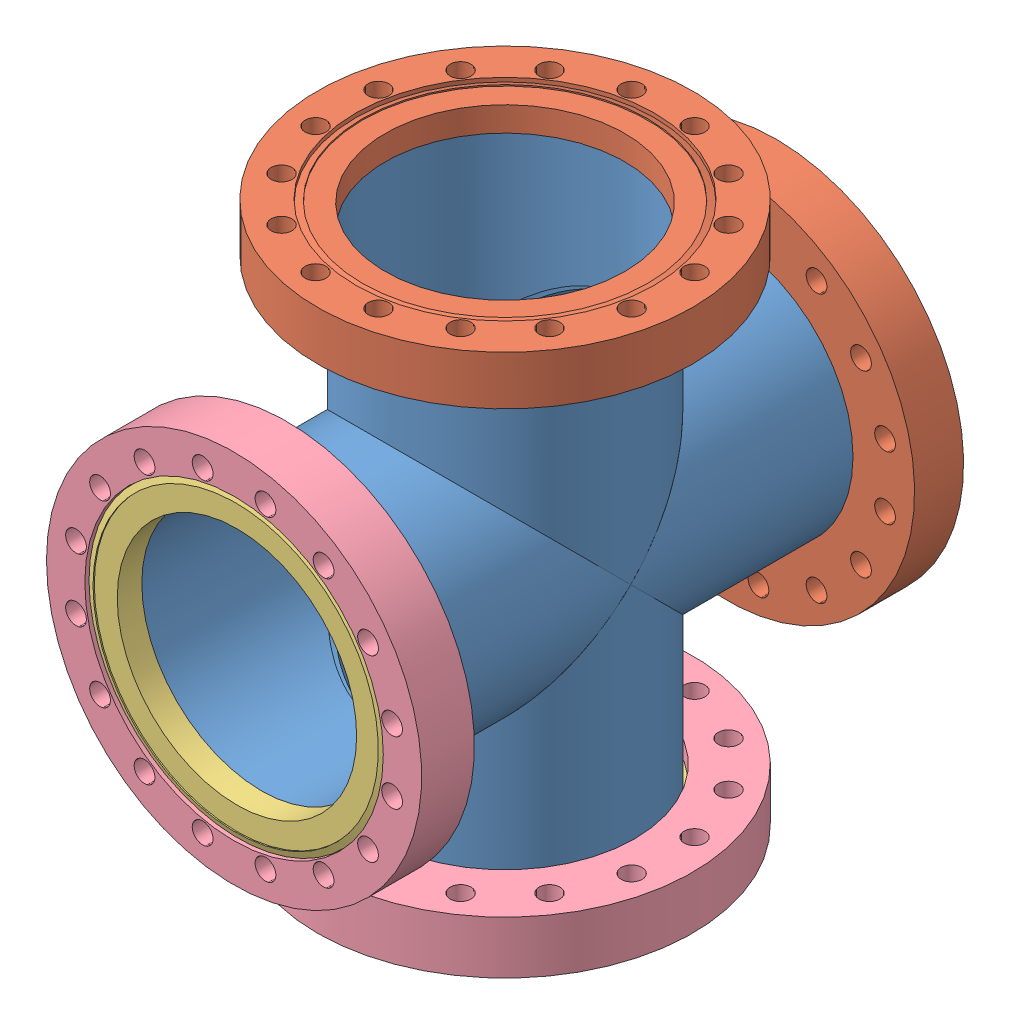
SolidWorks assembly 405033, configuration Default. Lengths in mm.
Overall size (151.64 219.05 219.05).
10 component instances, 4 part files, 0 mates.
Components (placement in the parent):
- 405033-001-1: 405033-001 [Default] at origin size (103.56 103.56 197.83)
- 405033-001-2: 405033-001 [Default] at (0 -98.425 98.425) x (1 0 0) z (0 1 0) size (103.56 103.56 197.83)
- 110026 (6.0 X 4.0 NR)-1: 110026 (6.0 X 4.0 NR) [Default] at (0 109.5248 98.425) x (0 -1 0) z (0 0 1) size (19.81 151.64 151.64)
- 110026 (6.0 X 4.0 NR)-2: 110026 (6.0 X 4.0 NR) [Default] at (0 0 -11.0998) x (0 0 1) z (-1 0 0) size (19.81 151.64 151.64)
- 100026 (6.0 X 4.0 R)-1: 100026 (6.0 X 4.0 R) [Default] at (0 0 193.6496) x (0 0 1) z (-1 0 0) size (21.34 151.64 151.64)
  - 100026 (6.0 X 4.0 INS)-1: 100026 (6.0 X 4.0 INS) [Default] at origin size (13.64 120.4 120.4)
  - 100026 (6.0 X 4.0 REC)-1: 100026 (6.0 X 4.0 REC) [Default] at (-7.0358 0 0) x (1 0 0) z (0 0 -1) size (21.34 151.64 151.64)
- 100026 (6.0 X 4.0 R)-2: 100026 (6.0 X 4.0 R) [Default] at (0 -95.2246 98.425) x (0 -1 0) z (0 0 1) size (21.34 151.64 151.64)
  - 100026 (6.0 X 4.0 INS)-1: 100026 (6.0 X 4.0 INS) [Default] at origin size (13.64 120.4 120.4)
  - 100026 (6.0 X 4.0 REC)-1: 100026 (6.0 X 4.0 REC) [Default] at (-7.0358 0 0) x (1 0 0) z (0 0 -1) size (21.34 151.64 151.64)
